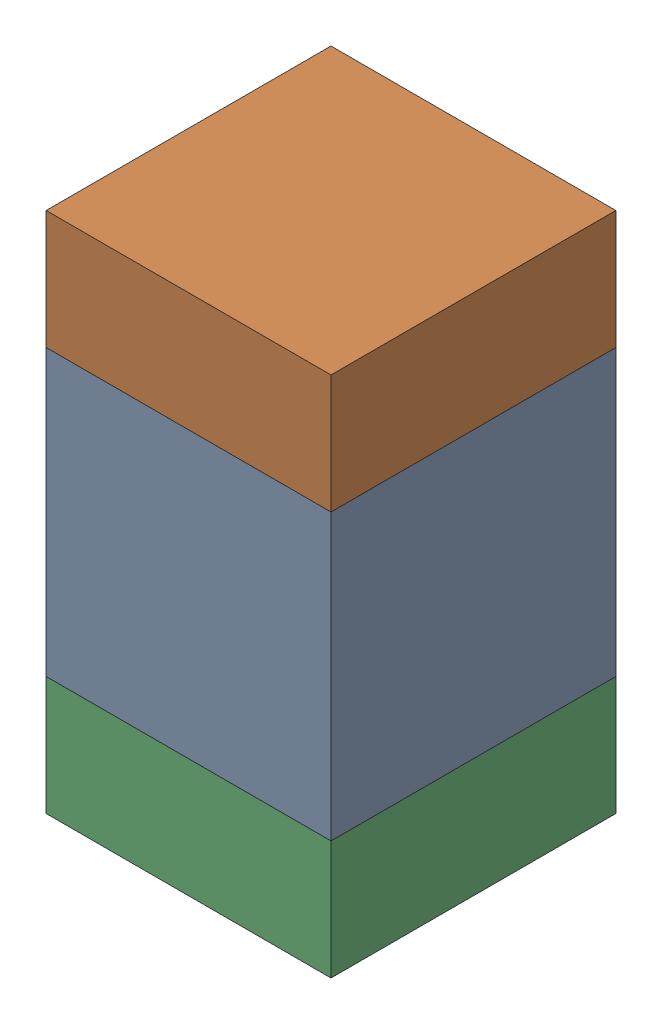
SolidWorks assembly C311_1PCB, configuration Default. Lengths in mm.
Overall size (0.6 1.1 0.6).
6 component instances, 2 part files, 0 mates.
Components (placement in the parent):
- 761606048-1: 761606048 [Default] at (144.9 105.3 0) size (0.6 0.6 0.6)
  - Extruded_9-1: Extruded_9 [Default] at origin size (0.6 0.6 0.6)
- 854785296-1: 854785296 [Default] at (144.9 105.725 0) size (0.6 0.25 0.6)
  - Extruded_10-1: Extruded_10 [Default] at origin size (0.6 0.25 0.6)
- 854785296-2: 854785296 [Default] at (144.9 104.875 0) size (0.6 0.25 0.6)
  - Extruded_10-1: Extruded_10 [Default] at origin size (0.6 0.25 0.6)
